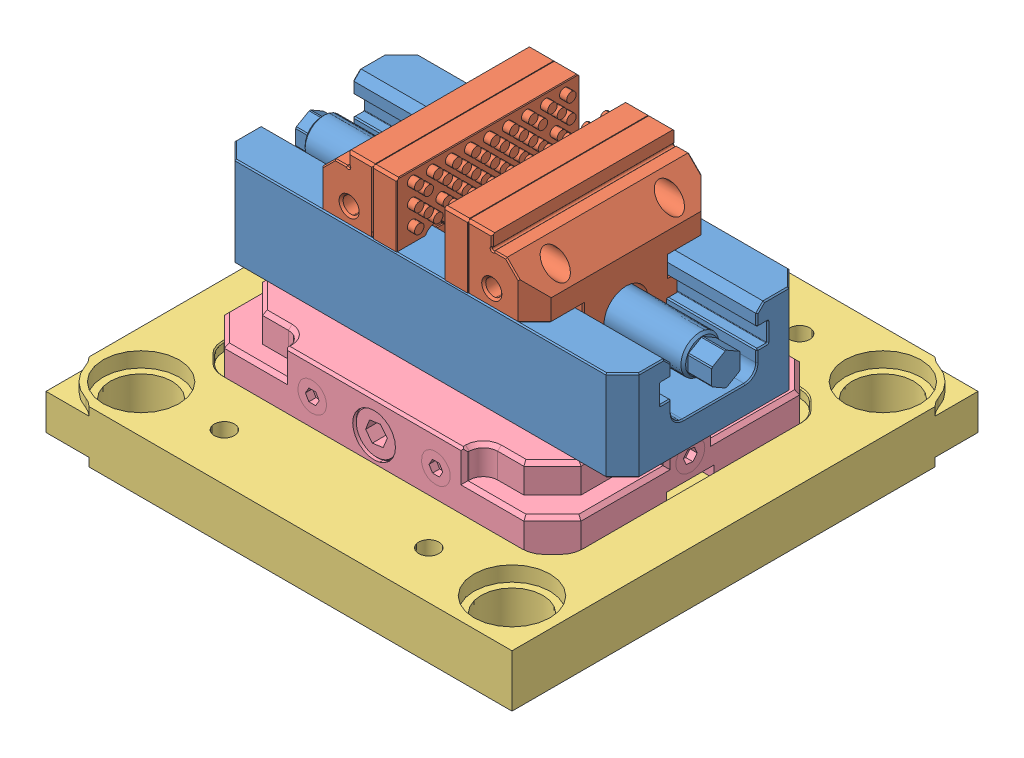
SolidWorks assembly ETAU VARIO 77x95 , configuration Défaut. Lengths in mm.
Overall size (196 166.1 206.23).
5 component instances, 4 part files, 12 mates.
Components (placement in the parent):
- Copie de 47160^ETAU VARIO 77x95 -1: Copie de 47160^ETAU VARIO 77x95  [Défaut] at origin size (175 60 77) (virtual)
- Copie de 42077-1101^ETAU VARIO 77x95 -1: Copie de 42077-1101^ETAU VARIO 77x95  [Défaut] at (20 26.34 0) x (0 0 1) z (-1 0 0) size (77 51 41) (hidden, virtual)
- Copie de 42077-1101^ETAU VARIO 77x95 -2: Copie de 42077-1101^ETAU VARIO 77x95  [Défaut] at (-20 26.34 0) x (0 0 -1) z (1 0 0) size (77 51 41) (virtual)
- Copie de F_50_196_196_22_1^ETAU VARIO 77x95 -1: Copie de F_50_196_196_22_1^ETAU VARIO 77x95  [Défaut] at (0 -23.2 0) x (1 0 0) z (0 1 0) size (196 196 22) (virtual)
- Copie de PLATEAU QUICKPOINT^ETAU VARIO 77x95 -1: Copie de PLATEAU QUICKPOINT^ETAU VARIO 77x95  [Défaut] at (0 -27 0) size (150 27 116) (virtual)
Mates (geometry in assembly coordinates):
- Coïncidente1: coincident anti-aligned: plane of Copie de 47160^ETAU VARIO 77x95 -1 through (-85 0 -38.5) normal (0 -1 0); plane of Copie de PLATEAU QUICKPOINT^ETAU VARIO 77x95 -1 through (75 0 58) normal (0 1 0)
- Coaxiale1: concentric aligned: cylinder of Copie de 47160^ETAU VARIO 77x95 -1 through (-26 4.9 -26) axis (0 1 0) radius 8; cylinder of Copie de PLATEAU QUICKPOINT^ETAU VARIO 77x95 -1 through (-26 -23 -26) axis (0 1 0) radius 8
- Parallèle1: parallel aligned: plane of Copie de 47160^ETAU VARIO 77x95 -1 through (-85 38 38.5) normal (0 0 1); plane of Copie de PLATEAU QUICKPOINT^ETAU VARIO 77x95 -1 through (-75 0 58) normal (0 0 1)
- Distance1: distance = 3.8 mm anti-aligned: plane of Copie de F_50_196_196_22_1^ETAU VARIO 77x95 -1 through (0 -23.2 0) normal (0 1 0); plane of Copie de PLATEAU QUICKPOINT^ETAU VARIO 77x95 -1 through (75 -27 58) normal (0 -1 0)
- Coïncidente5: coincident anti-aligned: plane of Copie de F_50_196_196_22_1^ETAU VARIO 77x95 -1 through (0 -23.2 0) normal (0 0 -1); plane of Copie de PLATEAU QUICKPOINT^ETAU VARIO 77x95 -1 through (0 -27 0) normal (0 0 1)
- Coïncidente7: coincident aligned: plane of Copie de F_50_196_196_22_1^ETAU VARIO 77x95 -1 through (0 -23.2 0) normal (1 0 0); plane of Copie de PLATEAU QUICKPOINT^ETAU VARIO 77x95 -1 through (0 -27 0) normal (1 0 0)
- Coïncidente8: coincident anti-aligned: plane of Copie de 47160^ETAU VARIO 77x95 -1 through (0 0 0) normal (0 0 1); plane of Copie de 42077-1101^ETAU VARIO 77x95 -2 through (-20 26.34 0) normal (0 0 -1)
- Coïncidente9: coincident aligned: plane of Copie de 47160^ETAU VARIO 77x95 -1 through (0 0 0) normal (0 0 1); plane of Copie de 42077-1101^ETAU VARIO 77x95 -1 through (20 26.34 0) normal (0 0 1)
- Coïncidente11: coincident anti-aligned: plane of Copie de 47160^ETAU VARIO 77x95 -1 through (-85 38 -38.5) normal (0 1 0); plane of Copie de 42077-1101^ETAU VARIO 77x95 -1 through (48 38 38.5) normal (0 -1 0)
- Coïncidente12: coincident anti-aligned: plane of Copie de 47160^ETAU VARIO 77x95 -1 through (-85 38 -38.5) normal (0 1 0); plane of Copie de 42077-1101^ETAU VARIO 77x95 -2 through (-48 38 38.5) normal (0 -1 0)
- Symétrique1: symmetric aligned: plane of Copie de 42077-1101^ETAU VARIO 77x95 -1 through (10 64.94 38.5) normal (-1 0 0); plane of Copie de 47160^ETAU VARIO 77x95 -1 through (-10 64.94 -38.5) normal (1 0 0); plane of Copie de 42077-1101^ETAU VARIO 77x95 -2 through (0 0 0) normal (1 0 0)
- Distance2: distance = 20 mm anti-aligned: plane of Copie de 42077-1101^ETAU VARIO 77x95 -2 through (-10 64.94 -38.5) normal (1 0 0); plane of Copie de 42077-1101^ETAU VARIO 77x95 -1 through (10 64.94 38.5) normal (-1 0 0)
